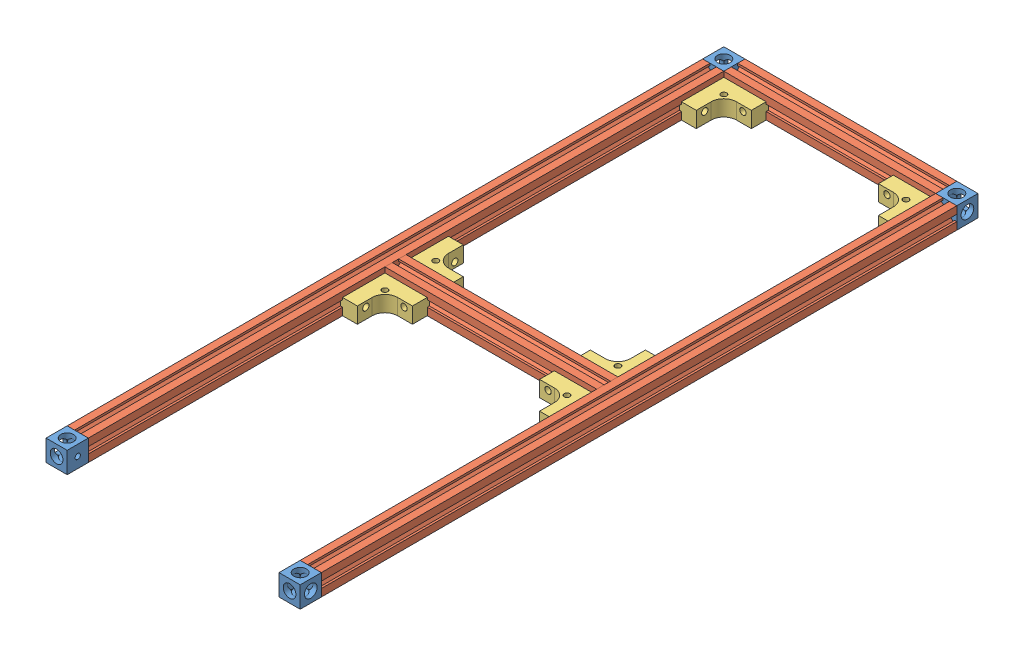
SolidWorks assembly BigRobotMakerBeamLeftFrame, configuration Default. Lengths in mm.
Overall size (120 10 320).
16 component instances, 3 part files, 15 mates.
Components (placement in the parent):
- BigRobotMakerBeamFrame-1: BigRobotMakerBeamFrame [Default] at (45.5821 193.9563 421.287) size (10 10 320)
  - MakerBeam-cube-1: MakerBeam-cube [Default] at (-29.6175 -5.1709 14.1418) size (10 10 10)
  - Makerbeam50-1000mm-1: Makerbeam50-1000mm [300mm] at (-29.6175 -5.1709 -285.8582) size (10 10 300)
  - MakerBeam-cube-2: MakerBeam-cube [Default] at (-34.6175 -5.1709 -290.8582) x (0 0 -1) z (1 0 0) size (10 10 10)
- BigRobotMakerBeamFrame-2: BigRobotMakerBeamFrame [Default] at (-99.2064 218.4029 421.287) x (0 1 0) z (0 0 1) size (10 10 320)
  - MakerBeam-cube-1: MakerBeam-cube [Default] at (-29.6175 -5.1709 14.1418) size (10 10 10)
  - Makerbeam50-1000mm-1: Makerbeam50-1000mm [300mm] at (-29.6175 -5.1709 -285.8582) size (10 10 300)
  - MakerBeam-cube-2: MakerBeam-cube [Default] at (-34.6175 -5.1709 -290.8582) x (0 0 -1) z (1 0 0) size (10 10 10)
- Makerbeam50-1000mm-1: Makerbeam50-1000mm [100mm] at (10.9645 188.7853 130.4289) x (0 1 0) z (-1 0 0) size (10 10 100)
- Bracket_L_Big_20x20_ForWindow-1: Bracket_L_Big_20x20_ForWindow [Default] at (-89.0355 183.7853 135.4289) x (0 0 1) z (0 1 0) size (21 21 7.5)
- Bracket_L_Big_20x20_ForWindow-2: Bracket_L_Big_20x20_ForWindow [Default] at (10.9645 183.7853 135.4289) x (-1 0 0) z (0 1 0) size (21 21 7.5)
- Makerbeam50-1000mm-2: Makerbeam50-1000mm [100mm] at (-89.0355 188.7853 290.4289) x (0 -1 0) z (1 0 0) size (10 10 100)
- Bracket_L_Big_20x20_ForWindow-3: Bracket_L_Big_20x20_ForWindow [Default] at (-89.0355 183.7853 295.4289) x (0 0 1) z (0 1 0) size (21 21 7.5)
- Bracket_L_Big_20x20_ForWindow-4: Bracket_L_Big_20x20_ForWindow [Default] at (10.9645 183.7853 295.4289) x (-1 0 0) z (0 1 0) size (21 21 7.5)
- Bracket_L_Big_20x20_ForWindow-5: Bracket_L_Big_20x20_ForWindow [Default] at (10.9645 191.2853 285.4289) x (-1 0 0) z (0 -1 0) size (21 21 7.5)
- Bracket_L_Big_20x20_ForWindow-6: Bracket_L_Big_20x20_ForWindow [Default] at (-89.0355 191.2853 285.4289) x (0 0 -1) z (0 -1 0) size (21 21 7.5)
Mates (geometry in assembly coordinates):
- Coincident1: coincident anti-aligned: plane of BigRobotMakerBeamFrame-2/MakerBeam-cube-2 through (-89.0355 193.7853 125.4289) normal (1 0 0); plane of Makerbeam50-1000mm-1 through (-89.0355 188.7853 130.4289) normal (-1 0 0)
- Coincident2: coincident aligned: plane of BigRobotMakerBeamFrame-2/MakerBeam-cube-2 through (-94.0355 193.7853 130.4289) normal (0 1 0); plane of Makerbeam50-1000mm-1 through (-89.0355 193.7853 125.4289) normal (0 1 0)
- Coincident3: coincident aligned: plane of BigRobotMakerBeamFrame-2/MakerBeam-cube-2 through (-89.0355 193.7853 125.4289) normal (0 0 -1); plane of Makerbeam50-1000mm-1 through (-89.0355 183.7853 125.4289) normal (0 0 -1)
- Coincident4: coincident anti-aligned: plane of BigRobotMakerBeamFrame-1/MakerBeam-cube-2 through (10.9645 188.7853 130.4289) normal (-1 0 0); plane of Makerbeam50-1000mm-1 through (10.9645 188.7853 130.4289) normal (1 0 0)
- Concentric2: concentric aligned: cylinder of BigRobotMakerBeamFrame-1/MakerBeam-cube-2 through (20.9645 188.7853 130.4289) axis (1 0 0) radius 1.25; cylinder of Makerbeam50-1000mm-1 through (-89.0355 188.7853 130.4289) axis (1 0 0) radius 1.25
- Coincident5: coincident aligned: plane of BigRobotMakerBeamFrame-1/MakerBeam-cube-2 through (20.9645 183.7853 125.4289) normal (0 0 -1); plane of Makerbeam50-1000mm-1 through (-89.0355 190.2853 125.4289) normal (0 0 -1)
- Coincident6: coincident aligned: plane of Makerbeam50-1000mm-1 through (-89.0355 183.7853 135.4289) normal (0 -1 0); plane of Bracket_L_Big_20x20_ForWindow-1 through (-76.0355 183.7853 148.4289) normal (0 -1 0)
- Coincident7: coincident anti-aligned: plane of Makerbeam50-1000mm-1 through (-89.0355 187.2853 135.4289) normal (0 0 1); plane of Bracket_L_Big_20x20_ForWindow-1 through (-69.0355 193.7853 135.4289) normal (0 0 -1)
- Coincident8: coincident anti-aligned: plane of BigRobotMakerBeamFrame-2/Makerbeam50-1000mm-1 through (-89.0355 187.2853 435.4289) normal (1 0 0); plane of Bracket_L_Big_20x20_ForWindow-1 through (-89.0355 193.7853 135.4289) normal (-1 0 0)
- Coincident9: coincident aligned: plane of BigRobotMakerBeamFrame-1/Makerbeam50-1000mm-1 through (14.4645 183.7853 435.4289) normal (0 -1 0); plane of Bracket_L_Big_20x20_ForWindow-2 through (-2.0355 183.7853 148.4289) normal (0 -1 0)
- Coincident10: coincident anti-aligned: plane of BigRobotMakerBeamFrame-1/Makerbeam50-1000mm-1 through (10.9645 190.2853 435.4289) normal (-1 0 0); plane of Bracket_L_Big_20x20_ForWindow-2 through (10.9645 193.7853 155.4289) normal (1 0 0)
- Coincident11: coincident anti-aligned: plane of Makerbeam50-1000mm-1 through (-89.0355 187.2853 135.4289) normal (0 0 1); plane of Bracket_L_Big_20x20_ForWindow-2 through (10.9645 193.7853 135.4289) normal (0 0 -1)
- Coincident12: coincident anti-aligned: plane of BigRobotMakerBeamFrame-1/Makerbeam50-1000mm-1 through (10.9645 183.7853 435.4289) normal (-1 0 0); plane of Makerbeam50-1000mm-2 through (10.9645 188.7853 290.4289) normal (1 0 0)
- Coincident13: coincident aligned: plane of BigRobotMakerBeamFrame-1/Makerbeam50-1000mm-1 through (14.4645 183.7853 435.4289) normal (0 -1 0); plane of Makerbeam50-1000mm-2 through (10.9645 183.7853 285.4289) normal (0 -1 0)
- Distance2: distance = 150 mm anti-aligned: plane of Makerbeam50-1000mm-2 through (10.9645 187.2853 285.4289) normal (0 0 -1); plane of Makerbeam50-1000mm-1 through (-89.0355 187.2853 135.4289) normal (0 0 1)
